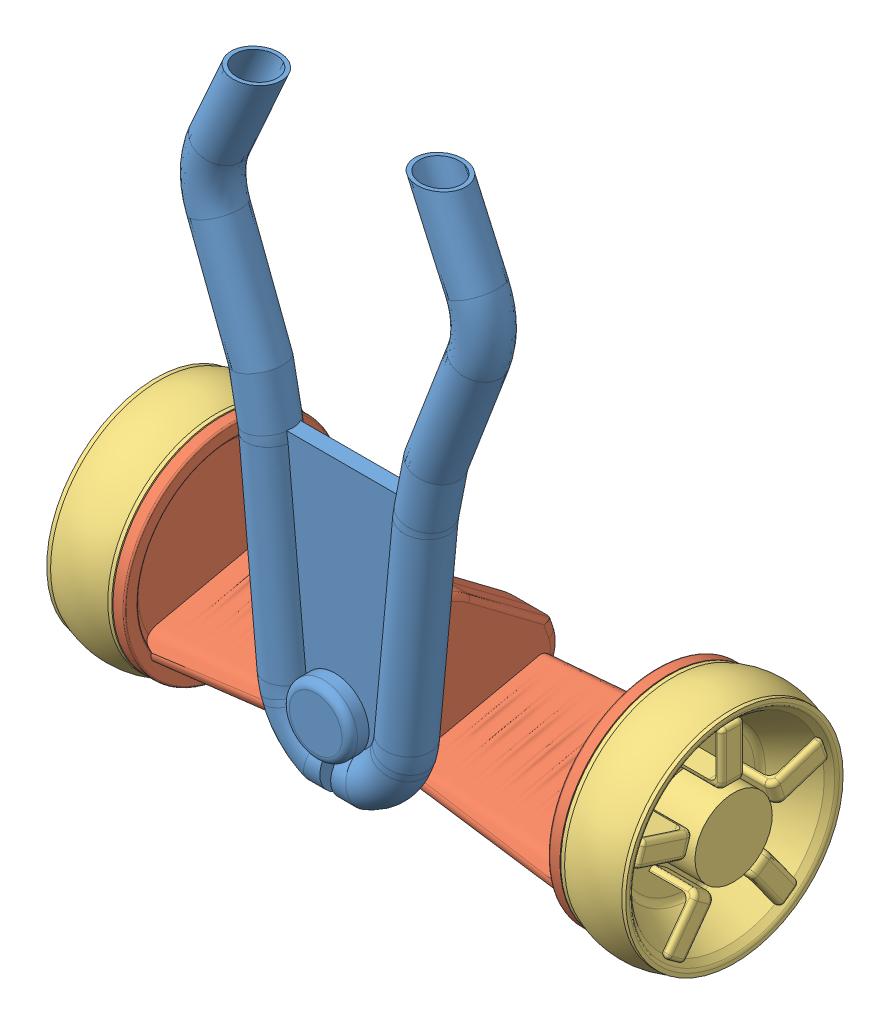
SolidWorks assembly Ensamblaje1, configuration Predeterminado. Lengths in mm.
Overall size (748.89 877.5 387.91).
4 component instances, 3 part files, 5 mates.
Components (placement in the parent):
- Manubrio-2: Manubrio [Predeterminado] at (-121.8858 -231.3819 751.5991) size (409.96 753.68 80.42)
- soporte-1: soporte [Predeterminado] at (-356.5558 -238.9279 623.7132) x (1 0 0) z (0 -0.213061 0.977039) size (593.9 296.28 280.72)
- Rueda-1: Rueda [Predeterminado] at (313.8004 -238.9279 623.7132) size (84.02 297.01 297.01)
- Rueda-2: Rueda [Predeterminado] at (-433.012 -238.9279 623.7132) x (-1 0 0) z (0 -0.924225 -0.381849) size (84.02 297.01 297.01)
Mates (geometry in assembly coordinates):
- Paralelo2: parallel anti-aligned: plane of Manubrio-2 through (-121.8858 -231.3819 713.4694) normal (0 0 -1); plane of soporte-1 through (237.3442 -238.9279 713.4694) normal (0 0 1)
- Paralelo3: parallel anti-aligned: plane of Manubrio-2 through (-121.8858 -231.3819 713.4694) normal (0 0 -1); plane of soporte-1 through (237.3442 -238.9279 713.4694) normal (0 0 1)
- CentroDePerfil1: profile center anti-aligned: plane of soporte-1 through (237.3442 -238.9279 713.4694) normal (0 0 1); plane of Manubrio-2 through (-121.8858 -231.3819 713.4694) normal (0 0 -1)
- CentroDePerfil2: profile center anti-aligned: plane of Rueda-1 through (237.3442 -238.9279 623.7132) normal (-1 0 0); plane of soporte-1 through (237.3442 -238.9279 623.7132) normal (1 0 0)
- CentroDePerfil4: profile center aligned: plane of soporte-1 through (-356.5558 -238.9279 623.7132) normal (-1 0 0); plane of Rueda-2 through (-356.5558 -238.9279 623.7132) normal (1 0 0)
